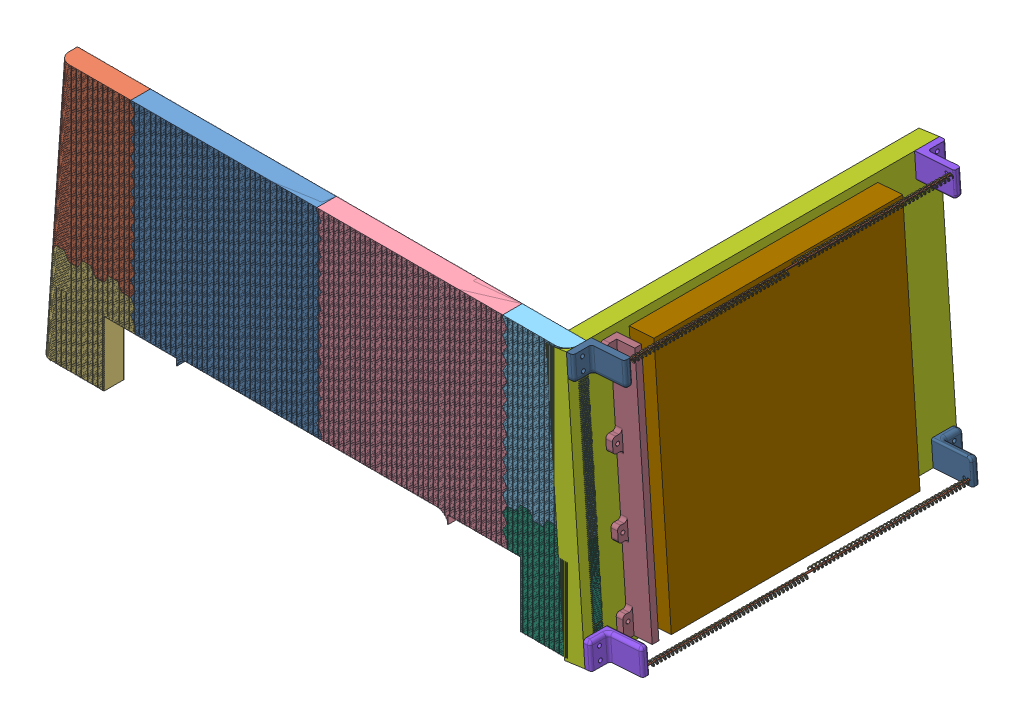
SolidWorks assembly murs_complets, configuration Default. Lengths in mm.
Overall size (729.04 333.52 450.01).
37 component instances, 13 part files, 6 mates.
Components (placement in the parent):
- mur_complete_gauche-droit-1: mur_complete_gauche-droit [Default] at (-202.9585 -307.3892 -476.3821) size (658.77 320.14 24)
  - mur_droit-gauche_split_1of2_subsplit_1of3-1: mur_droit-gauche_split_1of2_subsplit_1of3 [Default] at (144.11 306.1438 508.3312) size (600.69 249.99 24)
  - mur_droit-gauche_split_1of2_subsplit_2of3-1: mur_droit-gauche_split_1of2_subsplit_2of3 [Default] at (144.11 306.1438 508.3312) size (621.64 206.26 24)
  - mur_droit-gauche_split_1of2_subsplit_3of3-1: mur_droit-gauche_split_1of2_subsplit_3of3 [Default] at (144.11 306.1438 508.3312) size (630.07 320.77 24.57)
  - mur_droit-gauche_split_2of2_subsplit_1of3-1: mur_droit-gauche_split_2of2_subsplit_1of3 [Default] at (144.11 306.1438 508.3312) size (600.69 251.99 24)
  - mur_droit-gauche_split_2of2_subsplit_2of3-1: mur_droit-gauche_split_2of2_subsplit_2of3 [Default] at (144.11 306.1438 508.3312) size (621.22 197.14 24)
  - mur_droit-gauche_split_2of2_subsplit_3of3-1: mur_droit-gauche_split_2of2_subsplit_3of3 [Default] at (144.11 306.1438 508.3312) size (630.57 320.93 24.57)
- Radiateur-1: Radiateur [Default] at (292.592 -6.5887 -197.5689) x (0.990268 0.139173 0) z (0 0 1) size (95.68 323.35 450.01)
  - Radiateur.STEP-1: Radiateur.STEP [Default] at origin size (95.68 323.35 450.01)
    - Mur_largeur.STEP-1: Mur_largeur.STEP [Default] at (-64.9032 -140.3514 -216.6004) size (47.38 320 450)
    - braquetterad2.STEP-1: braquetterad2.STEP [Default] at (-39.9032 -140.3514 233.3996) x (0 0 -1) z (-0.069756 -0.997564 0) size (30 48 30)
    - 05-Radiateur.STEP-1: 05-Radiateur.STEP [Default] at (-9.2242 -131.689 158.3996) x (0.069756 0.997564 0) z (0 0 1) size (300 30 300)
    - braquetterad1.STEP-1: braquetterad1.STEP [Default] at (-19.6193 149.7217 233.3996) x (0 0 -1) z (-0.069756 -0.997564 0) size (30 48 30)
    - braquetterad2.STEP-2: braquetterad2.STEP [Default] at (-17.5266 179.6486 -216.6004) x (0 0 1) z (0.069756 0.997564 0) size (30 48 30)
    - braquetterad1.STEP-2: braquetterad1.STEP [Default] at (-37.8105 -110.4245 -216.6004) x (0 0 1) z (0.069756 0.997564 0) size (30 48 30)
    - tigerad.STEP-1: tigerad.STEP [Default] at (24.9501 170.6637 -191.6004) x (-0.267506 0.963556 0) z (0.963556 0.267506 0) size (2 400 2)
    - tigerad.STEP-2: tigerad.STEP [Default] at (3.4106 -137.3656 208.3996) x (1 0 0) z (0 1 0) size (2 400 2)
    - Springs.STEP-1: Springs.STEP [Default] at (0.7048 -136.4477 4.1759) x (1 0 0) z (0 0.999962 -0.008727) size (7 191 8.08)
    - Springs.STEP-2: Springs.STEP [Default] at (22.024 170.9453 1.098) x (1 0 0) z (0 0.999962 -0.008727) size (7 191 8.08)
    - Springs.STEP-3: Springs.STEP [Default] at (24.2732 170.9212 201.9899) x (1 0 0) z (0 0.999962 -0.008727) size (7 191 8.08)
    - Springs.STEP-4: Springs.STEP [Default] at (2.2292 -136.5481 199.8891) x (1 0 0) z (0 0.999962 -0.008727) size (7 191 8.08)
    - rightshield.STEP-1: rightshield.STEP [Default] at (-39.0719 -128.4631 173.3565) x (0.997564 -0.069756 0) z (-0.069756 -0.997564 0) size (30 20 300)
- Radiateur-2: Radiateur [Default] at (-405.5715 -6.5887 -181.1697) x (-0.990268 0.139173 0) z (0 0 -1) size (95.68 323.35 450.01) (hidden)
  - Radiateur.STEP-1: Radiateur.STEP [Default] at origin size (95.68 323.35 450.01)
    - Mur_largeur.STEP-1: Mur_largeur.STEP [Default] at (-64.9032 -140.3514 -216.6004) size (47.38 320 450)
    - braquetterad2.STEP-1: braquetterad2.STEP [Default] at (-39.9032 -140.3514 233.3996) x (0 0 -1) z (-0.069756 -0.997564 0) size (30 48 30)
    - 05-Radiateur.STEP-1: 05-Radiateur.STEP [Default] at (-9.2242 -131.689 158.3996) x (0.069756 0.997564 0) z (0 0 1) size (300 30 300)
    - braquetterad1.STEP-1: braquetterad1.STEP [Default] at (-19.6193 149.7217 233.3996) x (0 0 -1) z (-0.069756 -0.997564 0) size (30 48 30)
    - braquetterad2.STEP-2: braquetterad2.STEP [Default] at (-17.5266 179.6486 -216.6004) x (0 0 1) z (0.069756 0.997564 0) size (30 48 30)
    - braquetterad1.STEP-2: braquetterad1.STEP [Default] at (-37.8105 -110.4245 -216.6004) x (0 0 1) z (0.069756 0.997564 0) size (30 48 30)
    - tigerad.STEP-1: tigerad.STEP [Default] at (24.9501 170.6637 -191.6004) x (-0.267506 0.963556 0) z (0.963556 0.267506 0) size (2 400 2)
    - tigerad.STEP-2: tigerad.STEP [Default] at (3.4106 -137.3656 208.3996) x (1 0 0) z (0 1 0) size (2 400 2)
    - Springs.STEP-1: Springs.STEP [Default] at (0.7048 -136.4477 4.1759) x (1 0 0) z (0 0.999962 -0.008727) size (7 191 8.08)
    - Springs.STEP-2: Springs.STEP [Default] at (22.024 170.9453 1.098) x (1 0 0) z (0 0.999962 -0.008727) size (7 191 8.08)
    - Springs.STEP-3: Springs.STEP [Default] at (24.2732 170.9212 201.9899) x (1 0 0) z (0 0.999962 -0.008727) size (7 191 8.08)
    - Springs.STEP-4: Springs.STEP [Default] at (2.2292 -136.5481 199.8891) x (1 0 0) z (0 0.999962 -0.008727) size (7 191 8.08)
    - rightshield.STEP-1: rightshield.STEP [Default] at (-39.0719 -128.4631 173.3565) x (0.997564 -0.069756 0) z (-0.069756 -0.997564 0) size (30 20 300)
Mates (geometry in assembly coordinates):
- Coincident2: coincident: plane of mur_complete_gauche-droit-1/mur_droit-gauche_split_2of2_subsplit_1of3-1 through (236.7007 168.8723 12.2307) normal (0 1 0); line of Radiateur-1/Radiateur.STEP-1/Mur_largeur.STEP-1 through (250.2336 168.8723 35.8307) axis (0 0 -1)
- Coincident3: coincident aligned: plane of mur_complete_gauche-droit-1/mur_droit-gauche_split_2of2_subsplit_1of3-1 through (131.1514 -1.2453 35.8307) normal (0 0 1); plane of Radiateur-1/Radiateur.STEP-1/Mur_largeur.STEP-1 through (247.8535 -154.6071 35.8307) normal (0 0 1)
- Coincident4: coincident: plane of mur_complete_gauche-droit-1/mur_droit-gauche_split_1of2_subsplit_2of3-1 through (93.7854 -84.6277 35.4307) normal (0 0 1); plane of Radiateur-2/Radiateur.STEP-1/Mur_largeur.STEP-1 through (-360.9977 -156.9605 35.4307) normal (0 0 1)
- Coincident5: coincident: plane of mur_complete_gauche-droit-1/mur_droit-gauche_split_1of2_subsplit_2of3-1 through (-385.5898 -151.1277 12.2307) normal (-0.997564 0.069756 0); plane of Radiateur-2/Radiateur.STEP-1/Mur_largeur.STEP-1 through (-363.3778 166.5188 -414.5693) normal (-0.997564 0.069756 0)
- Parallel1: parallel: line of mur_complete_gauche-droit-1/mur_droit-gauche_split_1of2_subsplit_2of3-1 through (-363.4132 168.8723 22.0307) axis (0 0 -1); line of Radiateur-2/Radiateur.STEP-1/Mur_largeur.STEP-1 through (-363.3778 166.5188 -414.5693) axis (0 0 1)
- Coincident7: coincident: plane of mur_complete_gauche-droit-1/mur_droit-gauche_split_1of2_subsplit_2of3-1 through (236.7007 168.8723 12.2307) normal (0 1 0); line of Radiateur-2/Radiateur.STEP-1/Mur_largeur.STEP-1 through (-363.2132 168.8723 -414.5693) axis (0 0 1)
